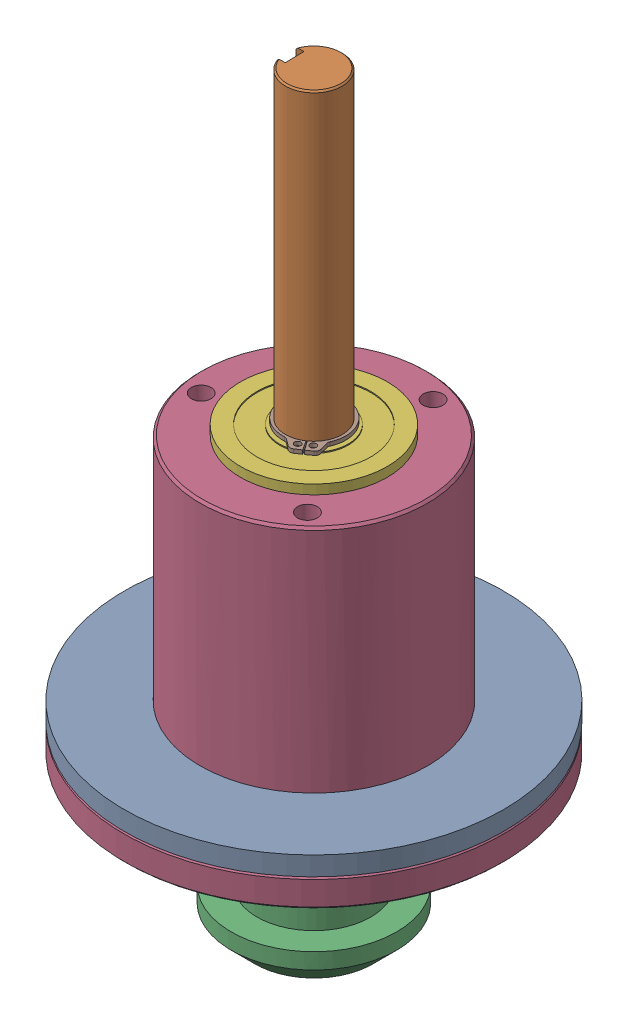
SolidWorks assembly cs_drive_hub_asm_1, configuration Default. Lengths in mm.
Overall size (89.7 127.05 89.7).
10 component instances, 8 part files, 0 mates.
Components (placement in the parent):
- 5906K526_thrust_bushing_1-1: 5906K526_thrust_bushing_1 [Default] at (33.9501 -89.5224 3.5116) x (-0.279506 0 -0.960144) z (0 -1 0) size (63.5 63.5 3.17)
- cs_vert_drive_shaft_1-1: cs_vert_drive_shaft_1 [Default] at (390.5574 -784.499 -2.4616) x (0 1 0) z (0.016748 0 0.99986) size (127.05 9.26 9.53)
- 6843K12_miter_gear_1-1: 6843K12_miter_gear_1 [Default] at (36.0118 -122.8345 2.5948) x (-0.91373 0 0.406323) z (-0.406323 0 -0.91373) size (27.69 19.05 27.69)
- revo2_pivot_hub-1: revo2_pivot_hub [Default] at (32.6196 -72.4841 4.7196) x (-0.740355 0 0.672216) z (-0.672216 0 -0.740355) size (63.5 46.42 63.5)
- brf-06_1-1: brf-06_1 [Default] at (33.9501 -95.4787 3.5116) x (-0.582551 0 0.812794) z (0 -1 0) size (24.59 24.59 7.11)
- brf-06_1-2: brf-06_1 [Default] at (33.9501 -53.0226 3.5116) x (-0.999614 0 -0.027772) z (0 1 0) size (24.59 24.59 7.11)
- Imported_1-1: Imported_1 [Default] at (33.9501 -123.279 3.5116) x (0 -1 0) z (0.051397 0 0.998678) size (0.64 12.09 10.6)
- Imported_1-2: Imported_1 [Default] at (33.9501 -49.0094 3.5116) x (0 1 0) z (0.82628 0 -0.563259) size (0.64 12.09 10.6)
- large_thrust_bushing_1-1: large_thrust_bushing_1 [Default] at (33.9501 -102.2097 3.5116) x (1 0 0) z (0 -1 0) size (19.05 19.05 1.57)
- bushing_backer_1-1: bushing_backer_1 [Default] at (33.9501 -99.0347 3.5116) x (1 0 0) z (0 -1 0) size (25.4 25.4 3.17)
